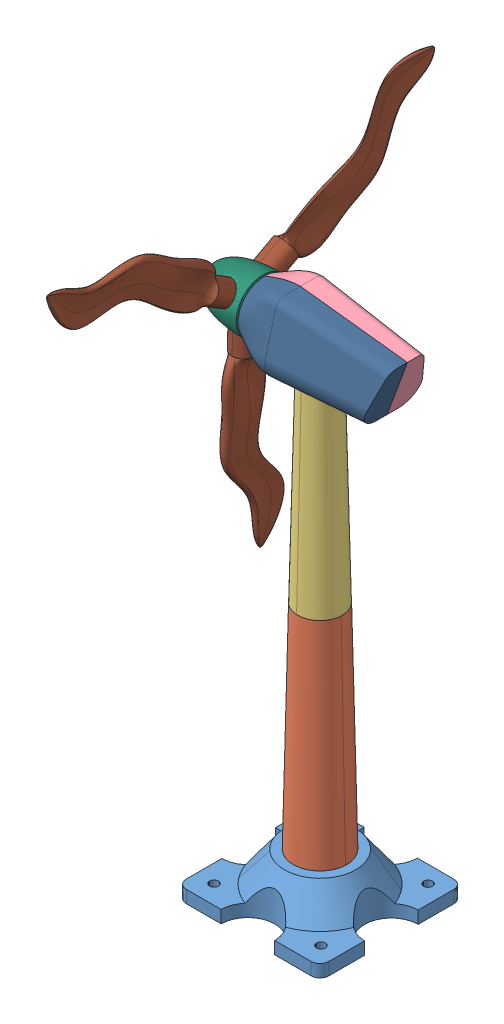
SolidWorks assembly Wind turbine assembly III (EXTERNAL RESULT) , configuration Default. Lengths in mm.
Overall size (140.98 456.4 306.35).
17 component instances, 11 part files, 0 mates.
Components (placement in the parent):
- Wind turbine assembly MARC2(cordinate).STEP-1: Wind turbine assembly MARC2(cordinate).STEP [Default] at origin size (140.98 456.4 306.35)
  - base.STEP-1: base.STEP [Default] at (78.4995 -345.44 -0.2668) x (-0.000714 0 1) z (-1 0 -0.000714) size (101.6 30.48 101.6)
  - Wind turbine lower mast.STEP-1: Wind turbine lower mast.STEP [Default] at (78.4995 -327.66 -0.2668) x (0 1 0) z (0.998658 0 0.051782) size (165.1 38.1 38.1)
  - Wind turbine upper mast.STEP-1: Wind turbine upper mast.STEP [Default] at (78.74 -175.26 0) x (0 1 0) z (-0.998658 0 -0.051782) size (152.4 31.75 31.75)
  - nacelle.STEP-1: nacelle.STEP [Default] at (64.77 0 0) x (0 0 1) z (-1 0 0) size (25.51 48.27 101.62)
  - connecting rod.STEP-1: connecting rod.STEP [Default] at (78.74 -29.21 0) x (-0.653528 0 0.756902) z (-0.756902 0 -0.653528) size (9.53 38.1 9.53)
  - Turbine Hub.STEP-1: Turbine Hub.STEP [Default] x (0 -0.031407 -0.999507) z (-1 0 0) size (41.13 38.1 38.1)
  - Turbine Hub.STEP-2: Turbine Hub.STEP [Default] x (0 0.881302 0.472554) z (-1 0 0) size (41.13 38.1 38.1)
  - Turbine Hub.STEP-3: Turbine Hub.STEP [Default] x (0 -0.849895 0.526953) z (-1 0 0) size (41.13 38.1 38.1)
  - 2780T350_HIGH-LOAD BEARING_2780T35.STEP-1: 2780T350_HIGH-LOAD BEARING_2780T35.STEP [Default] at (64.9287 0 0) x (0 0.911809 0.410615) z (-1 0 0) size (23.02 23.02 7.94)
  - 2780T350_HIGH-LOAD BEARING_2780T35.STEP-2: 2780T350_HIGH-LOAD BEARING_2780T35.STEP [Default] at (109.3787 0 0) x (0 -0.378851 0.925458) z (-1 0 0) size (23.02 23.02 7.94)
  - Turbine main shaft.STEP-1: Turbine main shaft.STEP [Default] at (73.025 0 0) x (0 -0.627713 -0.778445) z (0 -0.778445 0.627713) size (9.53 95.25 9.53)
  - 98408A134_SIDE-MOUNT EXTERNAL RETAINING RING  E-STYLE_98408A134.STEP-1: 98408A134_SIDE-MOUNT EXTERNAL RETAINING RING  E-STYLE_98408A134.STEP [Default] at (116.9919 0 0) size (0.89 16.76 15.36)
  - Mirrornacelle.STEP-1: Mirrornacelle.STEP [Default] at (64.77 0 0) x (0 0 -1) z (1 0 0) size (25.53 48.36 101.62)
  - rundwa wing(1).STEP-1: rundwa wing(1).STEP [Default] at (25.4 4.0154 6.4762) x (1 0 0) z (0 -0.849895 0.526953) size (19.03 151.58 60.38)
  - rundwa wing(1).STEP-2: rundwa wing(1).STEP [Default] at (25.4 3.6009 -6.7155) x (1 0 0) z (0 0.881302 0.472554) size (19.03 151.58 60.38)
  - rundwa wing(1).STEP-3: rundwa wing(1).STEP [Default] at (25.4 -7.6162 0.2393) x (1 0 0) z (0 -0.031407 -0.999507) size (19.03 151.58 60.38)
